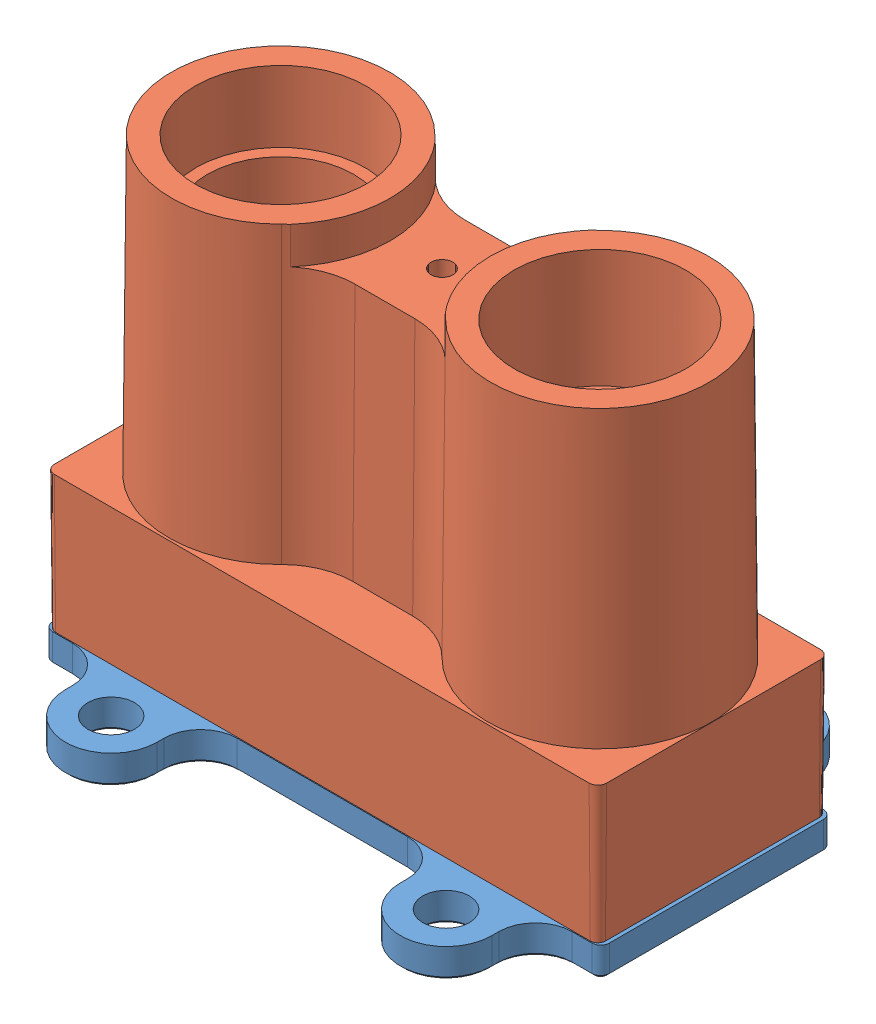
SolidWorks assembly LiDAR_Lite, configuration Default. Lengths in mm.
Overall size (48.26 39.85 35.56).
2 component instances, 2 part files, 5 mates.
Components (placement in the parent):
- LIDAR-Lite_Base-1: LIDAR-Lite_Base [Default] at (3.9982 4.445 0.3764) x (1 0 0) z (0 -1 0) size (48.26 35.56 5.72)
- LIDAR-Lite_Housing_RevD-1: LIDAR-Lite_Housing_RevD [Default] at (52.0437 2.54 8.1475) x (-1 0 0) z (0 1 0) size (47.88 20.07 37.31)
Mates (geometry in assembly coordinates):
- Coincident4: coincident anti-aligned: plane of LIDAR-Lite_Base-1 through (3.9982 2.54 0.3764) normal (0 1 0); plane of LIDAR-Lite_Housing_RevD-1 through (52.0437 2.54 28.2135) normal (0 -1 0)
- Concentric5: concentric anti-aligned: circle of LIDAR-Lite_Base-1; circle of LIDAR-Lite_Housing_RevD-1
- Concentric6: concentric anti-aligned: circle of LIDAR-Lite_Base-1; circle of LIDAR-Lite_Housing_RevD-1
- Concentric7: concentric anti-aligned: circle of LIDAR-Lite_Base-1; circle of LIDAR-Lite_Housing_RevD-1
- Coincident8: coincident anti-aligned: plane of LIDAR-Lite_Base-1 through (3.9982 0 35.9364) normal (0 -1 0); plane of assembly through (0 0 0) normal (0 1 0)
